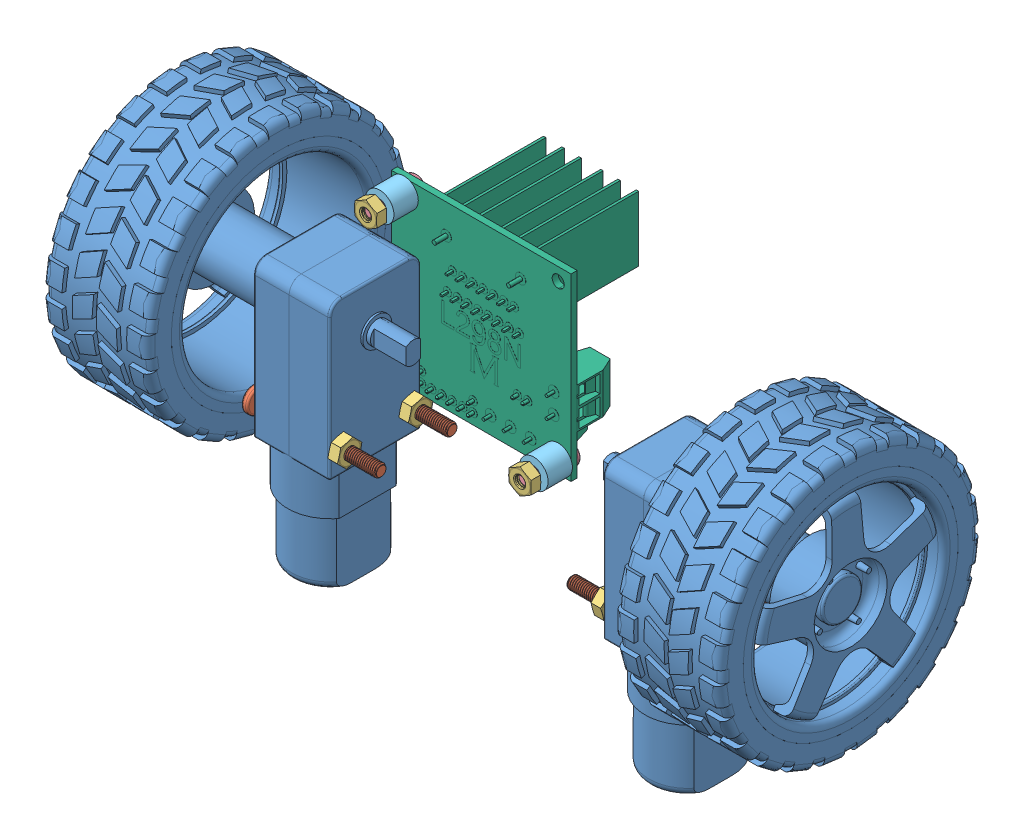
SolidWorks assembly CC2, configuration Predeterminado. Lengths in mm.
Overall size (167.22 100.48 91.74).
23 component instances, 6 part files, 10 mates.
Components (placement in the parent):
- smart_car_motor-7: smart_car_motor [Predeterminado] at (215.687 -153.6759 129.1904) x (1 0 0) z (0 -0.96637 0.257157) size (60.29 65 86.68)
  - dc_motor_with_wheel-1: dc_motor_with_wheel [Défaut] at (-4.5268 10.254 22.8405) size (59.31 65 86.68)
  - (M3_30_mm)_90116A155_METRIC 316 SS PAN HEAD PHILLIPS MACHINE SCREW-1: (M3_30_mm)_90116A155_METRIC 316 SS PAN HEAD PHILLIPS MACHINE SCREW [90116A155] at (-42.5488 8.3322 97.9978) x (0 0 -1) z (1 0 0) size (6 6 32.68)
  - (M3_30_mm)_90116A155_METRIC 316 SS PAN HEAD PHILLIPS MACHINE SCREW-2: (M3_30_mm)_90116A155_METRIC 316 SS PAN HEAD PHILLIPS MACHINE SCREW [90116A155] at (-42.5488 -8.5793 93.4976) x (0 0 -1) z (1 0 0) size (6 6 32.68)
  - M3 Nut-1: M3 Nut [Predeterminado] at (-30.8488 8.3322 97.9978) x (0 0 -1) z (1 0 0) size (6.27 6.27 2.71)
  - M3 Nut-2: M3 Nut [Predeterminado] at (-30.8488 -8.5793 93.4976) x (0 0 -1) z (1 0 0) size (6.27 6.27 2.71)
- smart_car_motor-8: smart_car_motor [Predeterminado] at (83.5895 -153.6759 178.196) x (-1 0 0) z (0 -0.96637 -0.257157) size (60.29 65 86.68)
  - dc_motor_with_wheel-1: dc_motor_with_wheel [Défaut] at (-4.5268 10.254 22.8405) size (59.31 65 86.68)
  - (M3_30_mm)_90116A155_METRIC 316 SS PAN HEAD PHILLIPS MACHINE SCREW-1: (M3_30_mm)_90116A155_METRIC 316 SS PAN HEAD PHILLIPS MACHINE SCREW [90116A155] at (-42.5488 8.3322 97.9978) x (0 0 -1) z (1 0 0) size (6 6 32.68)
  - (M3_30_mm)_90116A155_METRIC 316 SS PAN HEAD PHILLIPS MACHINE SCREW-2: (M3_30_mm)_90116A155_METRIC 316 SS PAN HEAD PHILLIPS MACHINE SCREW [90116A155] at (-42.5488 -8.5793 93.4976) x (0 0 -1) z (1 0 0) size (6 6 32.68)
  - M3 Nut-1: M3 Nut [Predeterminado] at (-30.8488 8.3322 97.9978) x (0 0 -1) z (1 0 0) size (6.27 6.27 2.71)
  - M3 Nut-2: M3 Nut [Predeterminado] at (-30.8488 -8.5793 93.4976) x (0 0 -1) z (1 0 0) size (6.27 6.27 2.71)
- L298N_spacer_screwM3-6: L298N_spacer_screwM3 [Predeterminado] at (117.6638 -187.1967 121.4851) x (-1 0 0) z (0 -1 0) size (46.24 12.93 46.24)
  - M3x10 Philips Screw-1: M3x10 Philips Screw [Predeterminado] at (-23.4745 -10.8043 63.32) x (1 0 0) z (0 1 0) size (5.3 5.3 11.8)
  - M3x10 Philips Screw-2: M3x10 Philips Screw [Predeterminado] at (14.5255 -10.8043 63.32) x (1 0 0) z (0 1 0) size (5.3 5.3 11.8)
  - M3x10 Philips Screw-3: M3x10 Philips Screw [Predeterminado] at (14.5255 -10.8043 25.32) x (1 0 0) z (0 1 0) size (5.3 5.3 11.8)
  - separador-1: separador [Predeterminado] at (14.5255 -12.3143 25.32) x (1 0 0) z (0 -1 0) size (7 7 6)
  - M3 Nut-1: M3 Nut [Predeterminado] at (14.5255 -23.3143 25.32) x (1 0 0) z (0 -1 0) size (6.27 6.27 2.71)
  - separador-2: separador [Predeterminado] at (-23.4745 -18.3143 63.32) x (0.472346 0 0.881413) z (0 1 0) size (7 7 6)
  - M3 Nut-2: M3 Nut [Predeterminado] at (-23.4745 -17.8143 63.32) x (1 0 0) z (0 1 0) size (6.27 6.27 2.71)
  - separador-3: separador [Predeterminado] at (14.5255 -12.3143 63.32) x (1 0 0) z (0 -1 0) size (7 7 6)
  - M3 Nut-3: M3 Nut [Predeterminado] at (14.5255 -23.3143 63.32) x (1 0 0) z (0 -1 0) size (6.27 6.27 2.71)
- L298N_M1-3: L298N_M1 [Predeterminado] at (143.6382 -253.3917 133.7994) x (-1 0 0) z (0 -1 0) size (44.32 29.51 44.32)
Mates (geometry in assembly coordinates):
- Coincidente393: coincident: plane of L298N_M1-3 through (99.9782 -253.6767 132.2894) normal (0 0 -1); plane of L298N_spacer_screwM3-6/M3x10 Philips Screw-3 through (103.1382 -210.9167 132.2894) normal (0 0 1)
- Concéntrica246: concentric: circle of L298N_M1-3; circle of L298N_spacer_screwM3-6/M3x10 Philips Screw-3
- Coincidente394: coincident: plane of L298N_M1-3 through (122.1382 -231.5167 133.7994) normal (0 0 1); plane of L298N_spacer_screwM3-6/separador-1 through (103.1382 -212.5167 133.7994) normal (0 0 -1)
- Concéntrica247: concentric: circle of L298N_M1-3; circle of L298N_spacer_screwM3-6/separador-1
- Coincidente395: coincident: plane of L298N_M1-3 through (99.9782 -253.6767 132.2894) normal (0 0 -1); plane of L298N_spacer_screwM3-6/M3x10 Philips Screw-1 through (141.1382 -248.9167 132.2894) normal (0 0 1)
- Coincidente396: coincident: plane of L298N_M1-3 through (122.1382 -231.5167 133.7994) normal (0 0 1); plane of L298N_spacer_screwM3-6/separador-2 through (141.1382 -250.5167 133.7994) normal (0 0 -1)
- Coincidente397: coincident: plane of L298N_M1-3 through (99.9782 -253.6767 132.2894) normal (0 0 -1); plane of L298N_spacer_screwM3-6/M3x10 Philips Screw-2 through (103.1382 -248.9167 132.2894) normal (0 0 1)
- Coincidente398: coincident: plane of L298N_M1-3 through (122.1382 -231.5167 133.7994) normal (0 0 1); plane of L298N_spacer_screwM3-6/separador-3 through (103.1382 -250.5167 133.7994) normal (0 0 -1)
- Concéntrica248: concentric: circle of L298N_M1-3; circle of L298N_spacer_screwM3-6/M3x10 Philips Screw-1
- Concéntrica249: concentric: circle of L298N_M1-3; circle of L298N_spacer_screwM3-6/M3x10 Philips Screw-2
